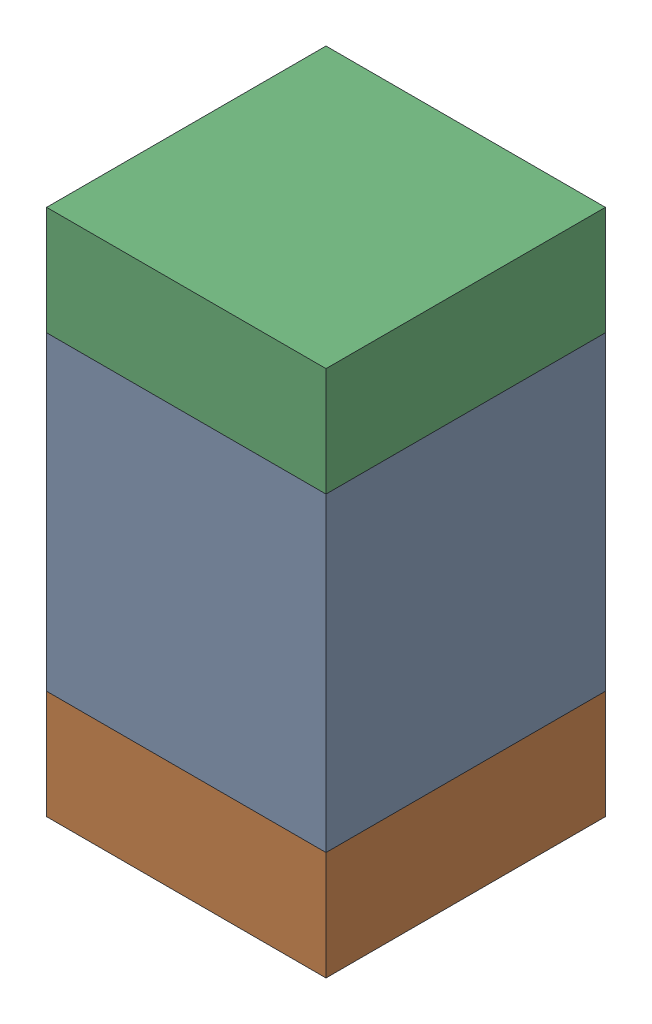
SolidWorks assembly C4, configuration Default. Lengths in mm.
Overall size (0.9 1.7 0.9).
6 component instances, 2 part files, 0 mates.
Components (placement in the parent):
- 5613956208-1: 5613956208 [Default] at (136.3 65.975 -2.5914) size (0.9 1 0.9)
  - Extruded_2-1: Extruded_2 [Default] at origin size (0.9 1 0.9)
- 5613953728-1: 5613953728 [Default] at (136.3 65.3 -2.5914) size (0.9 0.35 0.9)
  - Extruded_8-1: Extruded_8 [Default] at origin size (0.9 0.35 0.9)
- 5613953728-2: 5613953728 [Default] at (136.3 66.65 -2.5914) size (0.9 0.35 0.9)
  - Extruded_8-1: Extruded_8 [Default] at origin size (0.9 0.35 0.9)
